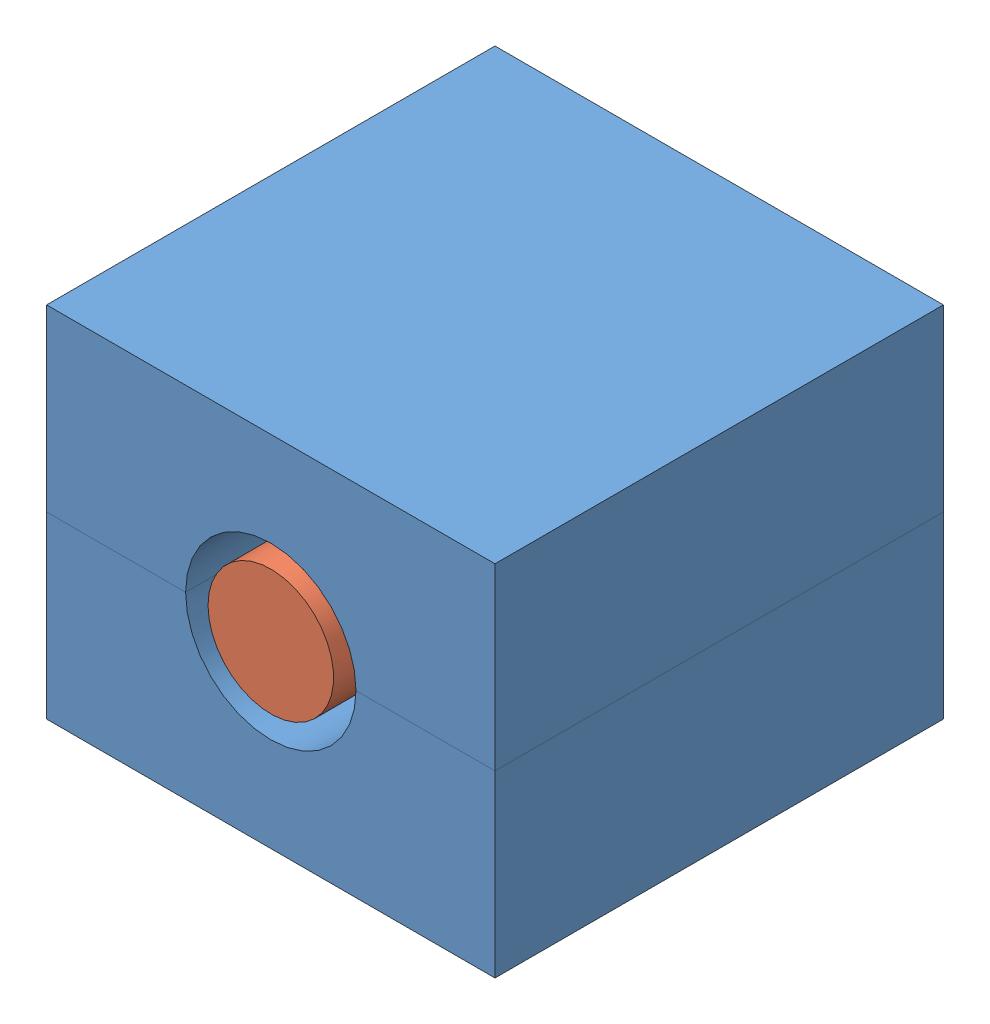
SolidWorks assembly Bellows-Mold-Assy, configuration Default. Lengths in mm.
Overall size (25 20 25).
3 component instances, 2 part files, 7 mates.
Components (placement in the parent):
- Bellows-cavity-half-1: Bellows-cavity-half [Default] at origin size (25 12 25)
- Bellows-cavity-half-2: Bellows-cavity-half [Default] at (0 20 0) x (-1 0 0) z (0 0 1) size (25 12 25)
- Bellows-core-1: Bellows-core [Default] at (0 10 0) x (1 0 0) z (0 1 0) size (7 21 7)
Mates (geometry in assembly coordinates):
- Coincident1: coincident anti-aligned: plane of Bellows-cavity-half-1 through (0 10 0) normal (0 1 0); plane of Bellows-cavity-half-2 through (0 10 0) normal (0 -1 0)
- Concentric1: concentric anti-aligned: cylinder of Bellows-cavity-half-1 through (7.5 7.5 -6.5) axis (0 1 0) radius 1.7; cone of Bellows-cavity-half-2 through (7.5 10 -6.5) axis (0 -1 0)
- Concentric2: concentric anti-aligned: cone of Bellows-cavity-half-1 through (-7.5 10 -6.5) axis (0 1 0); cylinder of Bellows-cavity-half-2 through (-7.5 12.5 -6.5) axis (0 -1 0) radius 1.7
- InPlace1: in place: plane of Bellows-cavity-half-1 through (0 10 0) normal (0 1 0); plane of Bellows-core-1 through (0 10 0) normal (0 1 0); moOrthogonalPlaneRef_w of Bellows-cavity-half-1 through (0 10 0) normal (0 1 0); plane of Bellows-core-1 through (0 10 0) normal (0 0 -1); plane of Bellows-cavity-half-1 through (0 10 0) normal (0 1 0); line of Bellows-core-1 through (-55 0 10) axis (0 1 0); plane of Bellows-cavity-half-1 through (0 10 0) normal (0 1 0); unknown of Bellows-core-1
- Coincident2: coincident aligned: plane of Bellows-cavity-half-1; plane of Bellows-core-1
- Coincident3: coincident aligned: moOrthogonalPlaneRef_w of Bellows-cavity-half-1 through (0 10 0) normal (0 0 -1); plane of Bellows-core-1 through (0 10 0) normal (0 0 -1)
- Coincident4: coincident anti-aligned: moOrthogonalPlaneRef_w of Bellows-cavity-half-1 through (0 10 0) normal (-1 0 0); plane of Bellows-core-1
